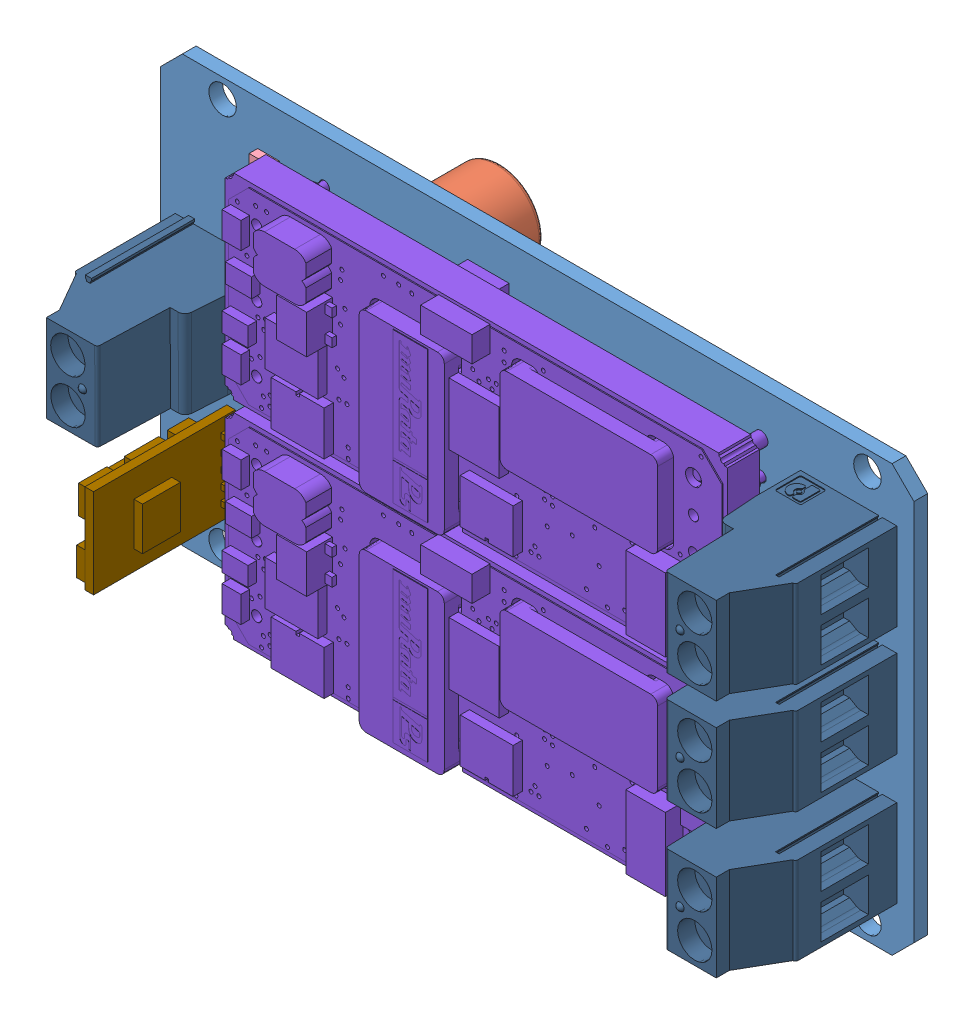
SolidWorks assembly carte_power, configuration Défaut. Lengths in mm.
Overall size (87.63 49.53 30.08).
18 component instances, 10 part files, 16 mates.
Components (placement in the parent):
- carte_power-1: carte_power [Défaut] at origin size (87.63 49.53 1.6)
- 153CLV-1010-1: 153CLV-1010 [Défaut] at (45.72 53.213 0) x (0 1 0) z (-1 0 0) size (10.3 10 10.3)
- 153CLV-1010-2: 153CLV-1010 [Défaut] at (45.847 36.195 0) x (-1 0 0) z (0 -1 0) size (10.3 10 10.3)
- 153CLV-1010-3: 153CLV-1010 [Défaut] at (45.974 24.765 0) x (-1 0 0) z (0 -1 0) size (10.3 10 10.3)
- C2012-1: C2012 [Default] at (83.439 50.8 0) x (0 -1 0) z (1 0 0) size (2.03 0.61 1.28)
- C2012-2: C2012 [Default] at (83.566 26.797 0) x (0 -1 0) z (1 0 0) size (2.03 0.61 1.28)
- C2012-3: C2012 [Default] at (83.566 16.764 0) x (0 1 0) z (-1 0 0) size (2.03 0.61 1.28)
- JP2_JP1_JP2-1: JP2_JP1_JP2 [Défaut] at (30.353 53.2765 1.6) x (0 1 0) z (0 0 1) size (7.7 2.54 1)
- JP2_JP2_JP2-1: JP2_JP2_JP2 [Défaut] at (30.48 29.9085 1.6) x (0 1 0) z (0 0 1) size (7.7 2.54 1)
- JP2_JP3_JP2-1: JP2_JP3_JP2 [Défaut] at (30.353 17.7165 1.6) x (0 1 0) z (0 0 1) size (7.7 2.54 1)
- R2012-1: R2012 [Default] at (27.051 29.972 0) x (-1 0 0) z (0 -1 0) size (2.03 0.61 1.28)
- UWE_12_6_Q12P_C-1: UWE_12_6_Q12P_C [Default] at (33.02 36.83 9.4608) x (1 0 0) z (0 0 -1) size (58.42 22.86 14.81)
- UWE_12_6_Q12P_C-2: UWE_12_6_Q12P_C [Default] at (33.02 60.96 9.4608) x (1 0 0) z (0 0 -1) size (58.42 22.86 14.81)
- TSR 3_2450-1: TSR 3_2450 [Default] at (25.9869 24.2642 9.85) x (0 -1 0) z (0 0 -1) size (10.4 6 19.8)
- Phoenix 2 poles-1: Phoenix 2 poles [Défaut] at (19.4948 45.7518 1.6) x (-0.999995 -0.003307 0) z (-0.003307 0.999995 0) size (11.2 23.48 10.73)
- Phoenix 2 poles-2: Phoenix 2 poles [Défaut] at (103.42 46.08 1.6) x (1 0 0) z (0 -1 0) size (11.2 23.48 10.73)
- Phoenix 2 poles-3: Phoenix 2 poles [Défaut] at (103.42 33.25 1.6) x (1 0 0) z (0 -1 0) size (11.2 23.48 10.73)
- Phoenix 2 poles-4: Phoenix 2 poles [Défaut] at (103.42 18.2 1.6) x (1 0 0) z (0 -1 0) size (11.2 23.48 10.73)
Mates (geometry in assembly coordinates):
- Coaxiale1: concentric anti-aligned: cylinder of carte_power-1 through (97.92 53.7 1.6) axis (0 0 -1) radius 0.66; cylinder of Phoenix 2 poles-2 through (97.92 53.7 1.6) axis (0 0 1) radius 0.65
- Coïncidente1: coincident anti-aligned: plane of carte_power-1 through (0 0 1.6) normal (0 0 1); plane of Phoenix 2 poles-2 through (94.963 50.7258 1.6) normal (0 0 -1)
- Coïncidente2: coincident anti-aligned: plane of carte_power-1 through (0 0 1.6) normal (0 0 1); plane of Phoenix 2 poles-3 through (94.963 37.8958 1.6) normal (0 0 -1)
- Coaxiale3: concentric anti-aligned: cylinder of carte_power-1 through (97.92 40.87 1.6) axis (0 0 -1) radius 0.66; cylinder of Phoenix 2 poles-3 through (97.92 40.87 1.6) axis (0 0 1) radius 0.65
- Coïncidente3: coincident anti-aligned: plane of carte_power-1 through (0 0 1.6) normal (0 0 1); plane of Phoenix 2 poles-4 through (94.963 22.8458 1.6) normal (0 0 -1)
- Coaxiale4: concentric anti-aligned: cylinder of carte_power-1 through (97.92 25.82 1.6) axis (0 0 -1) radius 0.66; cylinder of Phoenix 2 poles-4 through (97.92 25.82 1.6) axis (0 0 1) radius 0.65
- Coïncidente4: coincident anti-aligned: plane of carte_power-1 through (0 0 1.6) normal (0 0 1); plane of Phoenix 2 poles-1 through (27.9672 41.134 1.6) normal (0 0 -1)
- Coaxiale5: concentric anti-aligned: cylinder of carte_power-1 through (25.02 38.15 1.6) axis (0 0 -1) radius 0.66; cylinder of Phoenix 2 poles-1 through (25.02 38.15 1.6) axis (0 0 1) radius 0.65
- Distance1: distance = 4 mm anti-aligned: plane of carte_power-1 through (0 0 1.6) normal (0 0 1); plane of UWE_12_6_Q12P_C-1 through (59.8513 16.1695 5.6) normal (0 0 -1)
- Coaxiale6: concentric anti-aligned: cylinder of carte_power-1 through (36.83 33.02 1.6) axis (0 0 -1) radius 0.6; cylinder of UWE_12_6_Q12P_C-1 through (36.83 33.02 8.521) axis (0 0 1) radius 0.508
- Coaxiale7: concentric anti-aligned: cylinder of carte_power-1 through (87.63 33.02 1.6) axis (0 0 -1) radius 0.8; cylinder of UWE_12_6_Q12P_C-1 through (87.63 33.02 9.0036) axis (0 0 1) radius 0.7874
- Distance2: distance = 4 mm anti-aligned: plane of carte_power-1 through (0 0 1.6) normal (0 0 1); plane of UWE_12_6_Q12P_C-2 through (59.8513 40.2995 5.6) normal (0 0 -1)
- Coaxiale8: concentric anti-aligned: cylinder of carte_power-1 through (36.83 41.91 1.6) axis (0 0 -1) radius 0.6; cylinder of UWE_12_6_Q12P_C-2 through (36.83 41.91 8.521) axis (0 0 1) radius 0.508
- Coaxiale9: concentric anti-aligned: cylinder of carte_power-1 through (87.63 41.91 1.6) axis (0 0 -1) radius 0.8; cylinder of UWE_12_6_Q12P_C-2 through (87.63 41.91 9.0036) axis (0 0 1) radius 0.7874
- Coïncidente7: coincident anti-aligned: plane of carte_power-1 through (0 0 1.6) normal (0 0 1); plane of TSR 3_2450-1 through (25.4869 29.4642 1.6) normal (0 0 -1)
- Parallèle3: parallel aligned: plane of carte_power-1 through (17.78 15.24 1.6) normal (-1 0 0); plane of TSR 3_2450-1 through (25.4869 29.4642 1.6) normal (-1 0 0)
